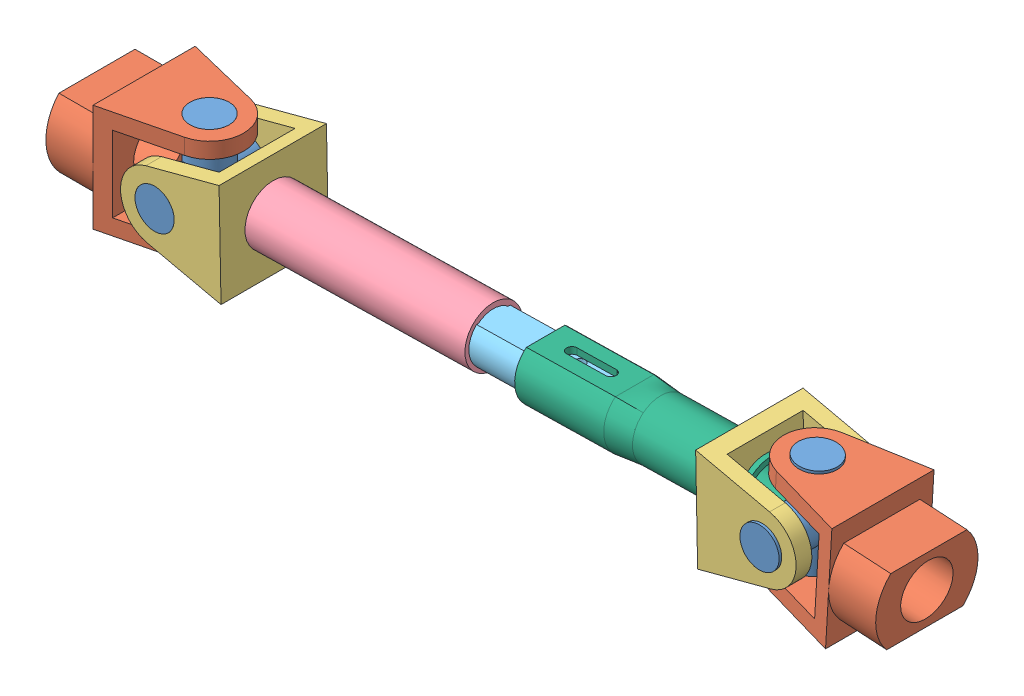
SolidWorks assembly RotulasUniversaisDireccao, configuration Default. Lengths in mm.
Overall size (319.12 52.55 43).
11 component instances, 6 part files, 3 mates.
Components (placement in the parent):
- JuntaUniversalInf-1: JuntaUniversalInf [Default] at (-114.6187 26.4157 42.5363) size (205.11 42 42)
  - Rotula-1: Rotula [Default] at (9.2327 -3.3638 -2.5866) size (15 42 42)
  - RotulaUniversalA-1: RotulaUniversalA [Default] at (-5.7673 -2.8638 -2.5866) size (56 41 39)
  - RotulaUniversalB-1: RotulaUniversalB [Default] at (24.2299 -3.0734 -2.0866) x (-0.999812 -0.019365 0) z (0.019365 -0.999812 0) size (38 41 39)
  - VeioRotulaInf-1: VeioRotulaInf [Default] at (-1.7653 -3.5768 -2.0866) x (0.999812 0.019365 0) z (-0.018362 0.948036 0.317632) size (92 22 22)
  - VeioAjusteFordCorsa-1: VeioAjusteFordCorsa [Default] at (132.2096 -0.982 -2.0866) x (0 0 1) z (0.019365 -0.999812 0) size (19 78 14)
- JuntaUniversalSup-1: JuntaUniversalSup [Default] at (145.0341 48.4853 79.8443) x (-0.998265 0.058883 0) z (0 0 1) size (146.54 42.4 42)
  - Rotula-1: Rotula [Default] at (17.1985 21.9918 -38.8946) x (-1 0 0) z (0 0 -1) size (15 42 42)
  - RotulaUniversalB-1: RotulaUniversalB [Default] at (32.1526 23.1648 -39.3946) x (-0.996937 -0.078203 0) z (-0.078203 0.996937 0) size (38 41 39)
  - VeioRotulaSup-1: VeioRotulaSup [Default] at (6.2322 21.1315 -39.3946) x (0.996937 0.078203 0) z (0 0 1) size (86 22.02 24.1)
  - RotulaUniversalA-1: RotulaUniversalA [Default] at (2.1985 22.4918 -38.8946) size (56 41 39)
Mates (geometry in assembly coordinates):
- Coincident3: coincident: plane of JuntaUniversalInf-1/VeioAjusteFordCorsa-1 through (-21.5373 31.6771 34.0271) normal (-0.019365 0.999812 0); plane of JuntaUniversalSup-1/VeioRotulaSup-1 through (88.0526 33.7997 46.8723) normal (0.019365 -0.999812 0)
- Concentric4: concentric: cylinder of JuntaUniversalInf-1/VeioAjusteFordCorsa-1 through (-21.4018 24.6785 40.4497) axis (0.999812 0.019365 0) radius 9.5; cylinder of JuntaUniversalSup-1/VeioRotulaSup-1 through (88.1881 26.801 40.4497) axis (-0.999812 -0.019365 0) radius 9.5
- Distance3: distance = 10 mm: cylinder of JuntaUniversalInf-1/VeioAjusteFordCorsa-1 through (36.7229 18.8029 40.4497) axis (0.019365 -0.999812 0) radius 2; line of JuntaUniversalSup-1/VeioRotulaSup-1 through (48.4011 35.5322 40.4497) axis (0.019365 -0.999812 0)
